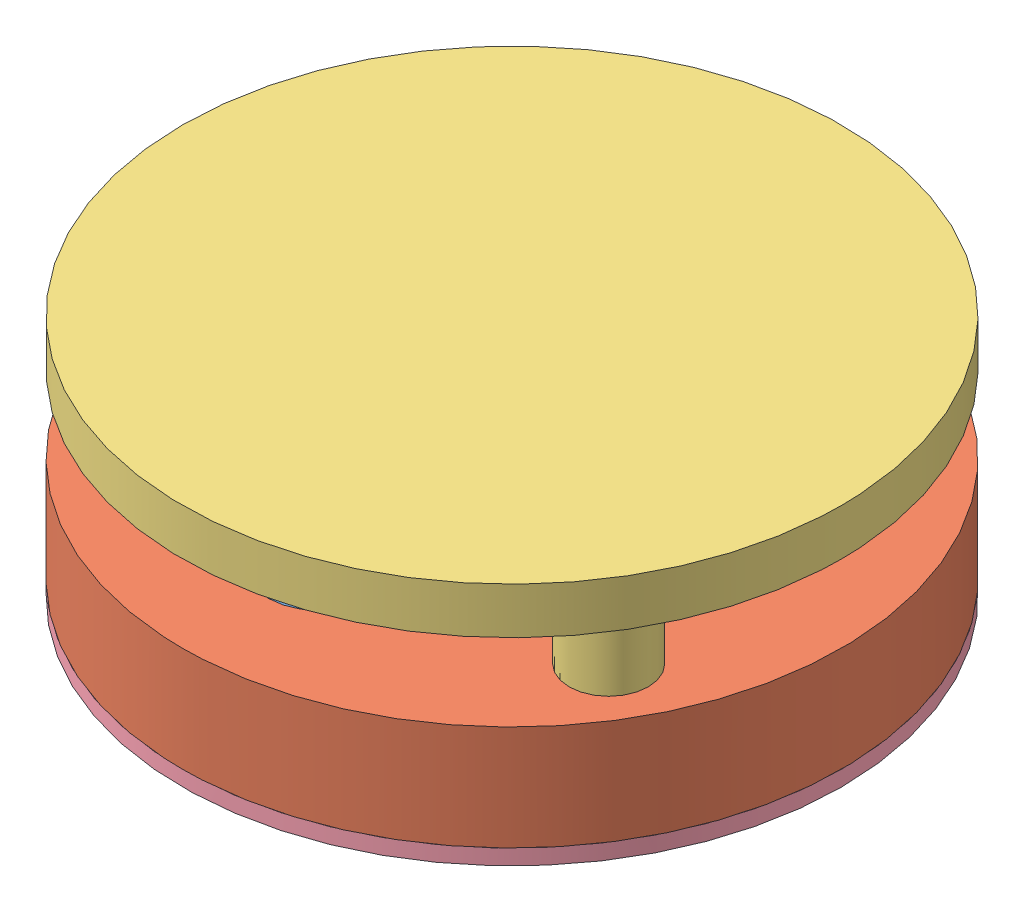
SolidWorks assembly ultrasonic_anemometer, configuration Default. Lengths in mm.
Overall size (85.23 33.1 85.23).
7 component instances, 4 part files, 14 mates.
Components (placement in the parent):
- ultrasonic_sensor_standalone-1: ultrasonic_sensor_standalone [Default] at (6.6322 6.3644 13.216) size (15.95 15.6 15.95)
- ua_body^ultrasonic_anemometer-1: ua_body^ultrasonic_anemometer [Default] at origin size (85.23 13.55 85.23) (virtual)
- ultrasonic_sensor_standalone-2: ultrasonic_sensor_standalone [Default] at (-15.0185 6.3644 0.716) size (15.95 15.6 15.95)
- ultrasonic_sensor_standalone-3: ultrasonic_sensor_standalone [Default] at (28.2828 6.3644 0.716) size (15.95 15.6 15.95)
- ultrasonic_sensor_standalone-4: ultrasonic_sensor_standalone [Default] at (6.6322 6.3644 38.216) size (15.95 15.6 15.95)
- ua_reflector^ultrasonic_anemometer-1: ua_reflector^ultrasonic_anemometer [Default] at (0 19.9144 0) x (1 0 0) z (0 1 0) size (85.23 85.23 28.2) (virtual)
- ua_lid^ultrasonic_anemometer-1: ua_lid^ultrasonic_anemometer [Default] at (0 6.3644 0) x (-1 0 0) z (0 -1 0) size (85.23 85.23 3.15) (virtual)
Mates (geometry in assembly coordinates):
- Concentric1: concentric aligned: circle of Part2^Assem1-1; circle of ultrasonic_sensor_standalone-2
- Coincident2: coincident aligned: plane of ultrasonic_sensor_standalone-1 through (6.6322 18.4144 13.216) normal (0 1 0); plane of ultrasonic_sensor_standalone-2 through (-15.0185 18.4144 0.716) normal (0 1 0)
- Concentric2: concentric aligned: circle of Part2^Assem1-1; circle of ultrasonic_sensor_standalone-3
- Coincident3: coincident aligned: plane of ultrasonic_sensor_standalone-1 through (6.6322 18.4144 13.216) normal (0 1 0); plane of ultrasonic_sensor_standalone-3 through (28.2828 18.4144 0.716) normal (0 1 0)
- Concentric3: concentric aligned: circle of Part2^Assem1-1; circle of ultrasonic_sensor_standalone-4
- Coincident4: coincident aligned: plane of ultrasonic_sensor_standalone-1 through (6.6322 18.4144 13.216) normal (0 1 0); plane of ultrasonic_sensor_standalone-4 through (6.6322 18.4144 38.216) normal (0 1 0)
- InPlace2: in place: plane of ua_body^ultrasonic_anemometer-1 through (6.6322 19.9144 13.216) normal (0 1 0); plane of ua_reflector^ultrasonic_anemometer-1 through (0 19.9144 0) normal (0 1 0); moOrthogonalPlaneRef_w of ua_body^ultrasonic_anemometer-1 through (6.6322 19.9144 13.216) normal (0 1 0); plane of ua_reflector^ultrasonic_anemometer-1 through (0 19.9144 0) normal (0 0 -1); plane of ua_body^ultrasonic_anemometer-1 through (6.6322 19.9144 13.216) normal (0 1 0); plane of ua_reflector^ultrasonic_anemometer-1 through (0 19.9144 0) normal (1 0 0); plane of ua_body^ultrasonic_anemometer-1 through (6.6322 19.9144 13.216) normal (0 1 0); unknown of ua_reflector^ultrasonic_anemometer-1
- Coincident8: coincident aligned: plane of ?; plane of ?
- Coincident9: coincident aligned: moOrthogonalPlaneRef_w of Part2^ultrasonic_anemometer-1 through (0 19.9144 0) normal (0 0 -1); plane of Part3^ultrasonic_anemometer-1 through (0 19.9144 0) normal (0 0 -1)
- Coincident10: coincident anti-aligned: moOrthogonalPlaneRef_w of Part2^ultrasonic_anemometer-1 through (0 19.9144 0) normal (-1 0 0); plane of Part3^ultrasonic_anemometer-1 through (0 19.9144 0) normal (1 0 0)
- InPlace4: in place: plane of ua_body^ultrasonic_anemometer-1 through (6.6322 6.3644 13.216) normal (0 -1 0); plane of ua_lid^ultrasonic_anemometer-1 through (0 6.3644 0) normal (0 -1 0); plane of ua_body^ultrasonic_anemometer-1 through (6.6322 6.3644 13.216) normal (0 -1 0); plane of ua_lid^ultrasonic_anemometer-1 through (0 6.3644 0) normal (0 0 -1); plane of ua_body^ultrasonic_anemometer-1 through (6.6322 6.3644 13.216) normal (0 -1 0); plane of ua_lid^ultrasonic_anemometer-1 through (0 6.3644 0) normal (-1 0 0); plane of ua_body^ultrasonic_anemometer-1 through (6.6322 6.3644 13.216) normal (0 -1 0); unknown of ua_lid^ultrasonic_anemometer-1
- Coincident14: coincident aligned: plane of ?; plane of ?
- Coincident15: coincident aligned: moOrthogonalPlaneRef_w of Part2^ultrasonic_anemometer-1 through (0 6.3644 0) normal (0 0 -1); plane of Part5^ultrasonic_anemometer-1 through (0 6.3644 0) normal (0 0 -1)
- Coincident16: coincident anti-aligned: moOrthogonalPlaneRef_w of Part2^ultrasonic_anemometer-1 through (0 6.3644 0) normal (1 0 0); plane of Part5^ultrasonic_anemometer-1 through (0 6.3644 0) normal (-1 0 0)
